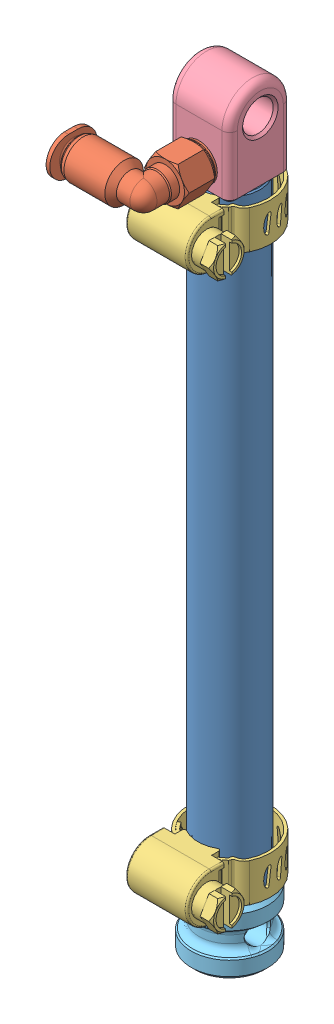
SolidWorks assembly AARL_QR_PN_PA_FL_WR_FL-Flexor, configuration Default. Lengths in mm.
Overall size (26.6 158.75 31.28).
6 component instances, 5 part files, 15 mates.
Components (placement in the parent):
- AARL_QR_PN_PA_FL_WR_FL_001-1: AARL_QR_PN_PA_FL_WR_FL_001 [Resting] at origin size (12.7 127 12.7)
- AARL_Puppy_18_02_57_010-QSML-M3-4-1: AARL_Puppy_18_02_57_010-QSML-M3-4 [Default] at (0 68.2625 17.85) x (-1 0 0) z (0 0 -1) size (20.32 8 18.9)
- AARL_Puppy_18_02_57_011-5388K140_Hose-Clamp-1: AARL_Puppy_18_02_57_011-5388K140_Hose-Clamp [5388K14] at (0 58.547 0) x (1 0 0) z (0 -1 0) size (19.43 23.71 9.91)
- AARL_Puppy_18_02_57_011-5388K140_Hose-Clamp-2: AARL_Puppy_18_02_57_011-5388K140_Hose-Clamp [5388K14] at (0 -58.547 0) x (1 0 0) z (0 -1 0) size (19.43 23.71 9.91)
- AARL_QR_PN_EP_001-1: AARL_QR_PN_EP_001 [Default] at (0 76.2 0) x (0 0 1) z (-1 0 0) size (12.7 31.75 12.7)
- AARL_QR_PN_EP_002-1: AARL_QR_PN_EP_002 [Default] at (0 -63.5 0) x (-1 0 0) z (0 0 1) size (15.88 25.4 15.88)
Mates (geometry in assembly coordinates):
- Concentric1: concentric aligned: cylinder of AARL_QR_PN_PA_FL_WR_FL_001-1 through (0 11.6086 0) axis (0 1 0) radius 4.7625; cylinder of AARL_QR_PN_EP_001-1 through (0 85.744 0) axis (0 1 0) radius 4.3656
- Parallel1: parallel aligned: plane of AARL_QR_PN_EP_001-1 through (-6.35 63.5 6.35) normal (0 0 1)
- Coincident2: coincident anti-aligned: plane of AARL_QR_PN_PA_FL_WR_FL_001-1 through (4.7625 63.5 0) normal (0 1 0); plane of AARL_QR_PN_EP_001-1 through (-6.35 63.5 -6.35) normal (0 -1 0)
- Concentric2: concentric anti-aligned: cylinder of AARL_QR_PN_PA_FL_WR_FL_001-1 through (0 11.6086 0) axis (0 1 0) radius 4.7625; cylinder of AARL_QR_PN_EP_002-1 through (0 -71.2377 0) axis (0 -1 0) radius 4.3656
- Coincident3: coincident anti-aligned: plane of AARL_QR_PN_PA_FL_WR_FL_001-1 through (6.35 -63.5 0) normal (0 -1 0); plane of AARL_QR_PN_EP_002-1 through (-4.3656 -63.5 0) normal (0 1 0)
- Parallel2: parallel anti-aligned: cylinder of AARL_QR_PN_EP_001-1 through (-6.35 76.2 0) axis (1 0 0) radius 3.175; cylinder of AARL_QR_PN_EP_002-1 through (7.9375 -69.85 0) axis (-1 0 0) radius 2.3813
- Concentric4: concentric aligned: cylinder of AARL_Puppy_18_02_57_010-QSML-M3-4-1 through (0 68.2625 6.35) axis (0 0 1) radius 1.5; cylinder of AARL_QR_PN_EP_001-1 through (0 68.2625 6.35) axis (0 0 1) radius 2.0193
- Coincident4: coincident anti-aligned: plane of AARL_Puppy_18_02_57_010-QSML-M3-4-1 through (0 68.2625 6.35) normal (0 0 -1); plane of AARL_QR_PN_EP_001-1 through (-6.35 63.5 6.35) normal (0 0 1)
- Parallel3: parallel aligned: plane of AARL_Puppy_18_02_57_010-QSML-M3-4-1 through (2.3094 64.2625 13.4056) normal (0 -1 0); plane of AARL_QR_PN_EP_001-1 through (-6.35 63.5 -6.35) normal (0 -1 0)
- Concentric5: concentric aligned: cylinder of AARL_QR_PN_PA_FL_WR_FL_001-1 through (0 11.6086 0) axis (0 1 0) radius 6.35; cylinder of AARL_Puppy_18_02_57_011-5388K140_Hose-Clamp-1 through (0 54.5783 0) axis (0 1 0) radius 7.9375
- Coincident6: coincident aligned: plane of AARL_Puppy_18_02_57_011-5388K140_Hose-Clamp-1 through (6.35 58.547 10.2337) normal (1 0 0); plane of AARL_QR_PN_EP_001-1 through (6.35 76.2 0) normal (1 0 0)
- Coincident7: coincident anti-aligned: plane of AARL_Puppy_18_02_57_011-5388K140_Hose-Clamp-1 through (0 63.5 0) normal (0 1 0); plane of AARL_QR_PN_EP_001-1 through (-6.35 63.5 -6.35) normal (0 -1 0)
- Concentric6: concentric aligned: cylinder of AARL_QR_PN_PA_FL_WR_FL_001-1 through (0 11.6086 0) axis (0 1 0) radius 6.35; cylinder of AARL_Puppy_18_02_57_011-5388K140_Hose-Clamp-2 through (0 -62.5157 0) axis (0 1 0) radius 7.9375
- Coincident8: coincident aligned: plane of AARL_Puppy_18_02_57_011-5388K140_Hose-Clamp-1 through (6.35 58.547 10.2337) normal (1 0 0); plane of AARL_Puppy_18_02_57_011-5388K140_Hose-Clamp-2 through (6.35 -58.547 10.2337) normal (1 0 0)
- Coincident9: coincident anti-aligned: plane of AARL_Puppy_18_02_57_011-5388K140_Hose-Clamp-2 through (0 -63.5 0) normal (0 -1 0); plane of AARL_QR_PN_EP_002-1 through (-4.3656 -63.5 0) normal (0 1 0)
